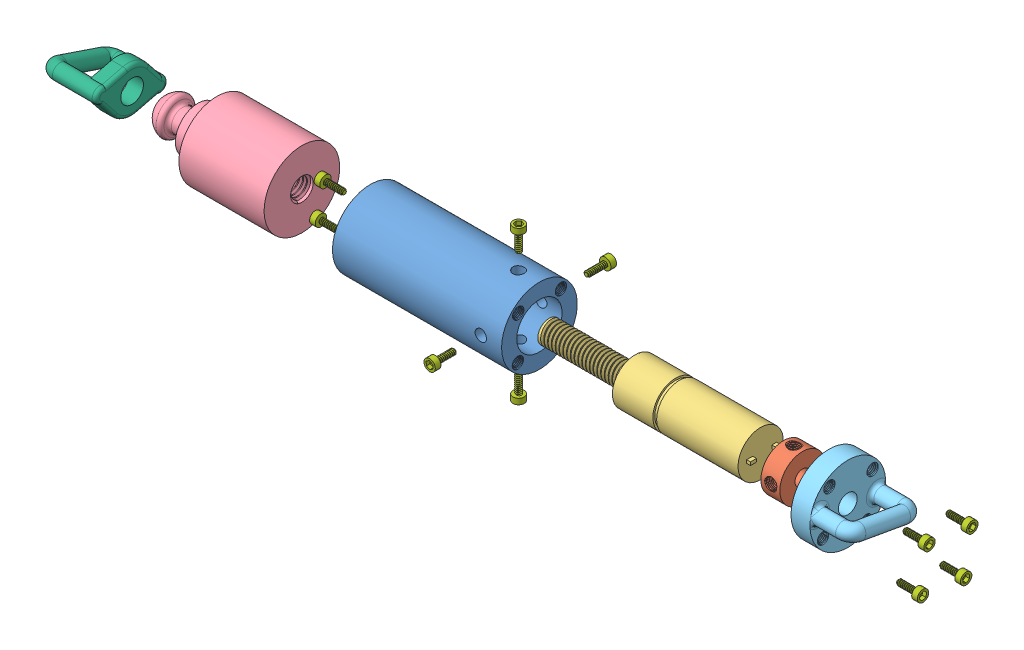
SolidWorks assembly Ensamblaje original, configuration Predeterminado. Lengths in mm.
Overall size (231.08 40.39 47.92).
16 component instances, 7 part files, 17 mates.
Components (placement in the parent):
- Elemento 1-1: Elemento 1 [Predeterminado] at (-42.454 6.1684 44.721) size (44.72 20 20)
- Elemento 2-1: Elemento 2 [Predeterminado] at (66.7772 6.1684 44.721) x (1 0 0) z (0 -0.9988 0.048973) size (5 12.09 12.06)
- Elemento 3-1: Elemento 3 [Predeterminado] at (63.7159 6.1684 44.721) x (-1 0 0) z (0 -1 0) size (57.07 12 12)
- Elemento 4-1: Elemento 4 [Predeterminado] at (-60.523 6.0408 44.721) x (-1 0 0) z (0 0.920881 -0.389844) size (37.67 20 20)
- Elemento 5-1: Elemento 5 [Predeterminado] at (78.7455 6.1684 44.721) x (1 0 0) z (0 0.174552 0.984648) size (15.81 20 20)
- Elemento 6-1: Elemento 6 [Predeterminado] at (-105.3931 6.0408 44.721) x (-1 0 0) z (0 0.321085 0.947051) size (15.5 12.01 20.01)
- Tornillo-2: Tornillo [Predeterminado] at (-3.254 6.1684 20.3258) x (0 0 1) z (-0.99419 -0.107636 0) size (6.53 3 3)
- Tornillo-3: Tornillo [Predeterminado] at (-3.254 6.1684 68.2422) x (0 0 -1) z (0.285128 -0.958489 0) size (6.53 3 3)
- Tornillo-4: Tornillo [Predeterminado] at (-3.254 26.7761 44.721) x (0 -1 0) z (0.385697 0 0.922626) size (6.53 3 3)
- Tornillo-6: Tornillo [Predeterminado] at (-3.254 -13.6157 44.721) x (0 1 0) z (0 0 1) size (6.53 3 3)
- Tornillo-7: Tornillo [Predeterminado] at (110.103 10.7454 38.1715) x (-1 0 0) z (0 0 -1) size (6.53 3 3)
- Tornillo-8: Tornillo [Predeterminado] at (110.1506 -0.1662 39.8509) x (-1 0 0) z (0 -0.269093 -0.963114) size (6.53 3 3)
- Tornillo-9: Tornillo [Predeterminado] at (110.1767 1.5914 51.2705) x (-1 0 0) z (0 -0.539826 -0.841777) size (6.53 3 3)
- Tornillo-10: Tornillo [Predeterminado] at (110.1877 12.503 49.5911) x (-1 0 0) z (0 -0.345496 -0.93842) size (6.53 3 3)
- Tornillo-13: Tornillo [Predeterminado] at (-55.7798 10.9184 44.721) size (6.53 3 3)
- Tornillo-14: Tornillo [Predeterminado] at (-56.9935 1.4184 44.721) x (1 0 0) z (0 -0.491861 0.870674) size (6.53 3 3)
Mates (geometry in assembly coordinates):
- Concéntrica2: concentric aligned: circle of Elemento 1-1; circle of Elemento 3-1
- Concéntrica3: concentric anti-aligned: circle of Elemento 1-1; circle of Elemento 3-1
- Concéntrica4: concentric anti-aligned: circle of Elemento 3-1; circle of Elemento 4-1
- Concéntrica5: concentric anti-aligned: cylinder of Elemento 1-1 through (-39.454 6.1684 44.721) axis (1 0 0) radius 6; cylinder of Elemento 2-1 through (71.7772 6.1684 44.721) axis (-1 0 0) radius 6
- Concéntrica7: concentric aligned: circle of Elemento 1-1; circle of Elemento 5-1
- Concéntrica8: concentric aligned: cylinder of Elemento 4-1 through (-93.023 6.0408 44.721) axis (1 0 0) radius 3; cylinder of Elemento 6-1 through (-109.3931 6.0408 44.721) axis (1 0 0) radius 3
- Coincidente6: coincident aligned: cylinder of Elemento 1-1 through (-3.254 6.1684 38.9115) axis (0 0 1) radius 1.5; circle of Tornillo-2
- Coincidente8: coincident anti-aligned: cylinder of Elemento 1-1 through (-3.254 6.1684 54.721) axis (0 0 1) radius 1.5; circle of Tornillo-3
- Concéntrica10: concentric aligned: cylinder of Elemento 1-1 through (-3.254 11.9779 44.721) axis (0 -1 0) radius 1.5; cylinder of Tornillo-4 through (-3.254 20.2761 44.721) axis (0 -1 0) radius 1.5
- Concéntrica12: concentric aligned: cylinder of Elemento 1-1 through (-3.254 0.3589 44.721) axis (0 1 0) radius 1.5; cylinder of Tornillo-6 through (-3.254 -7.1157 44.721) axis (0 1 0) radius 1.5
- Coincidente10: coincident anti-aligned: circle of Elemento 5-1; cylinder of Tornillo-10 through (103.6877 12.503 49.5911) axis (-1 0 0) radius 1.5
- Coincidente11: coincident anti-aligned: circle of Elemento 5-1; cylinder of Tornillo-7 through (103.603 10.7454 38.1715) axis (-1 0 0) radius 1.5
- Coincidente12: coincident anti-aligned: circle of Elemento 5-1; cylinder of Tornillo-9 through (103.6767 1.5914 51.2705) axis (-1 0 0) radius 1.5
- Coincidente13: coincident anti-aligned: circle of Elemento 5-1; cylinder of Tornillo-8 through (103.6506 -0.1662 39.8509) axis (-1 0 0) radius 1.5
- Bloquear1: lock: unknown of Elemento 1-1; unknown of ?
- Concéntrica14: concentric anti-aligned: circle of Elemento 1-1; cylinder of Tornillo-13 through (-49.2798 10.9184 44.721) axis (1 0 0) radius 1.5
- Concéntrica15: concentric anti-aligned: circle of Elemento 1-1; cylinder of Tornillo-14 through (-50.4935 1.4184 44.721) axis (1 0 0) radius 1.5
